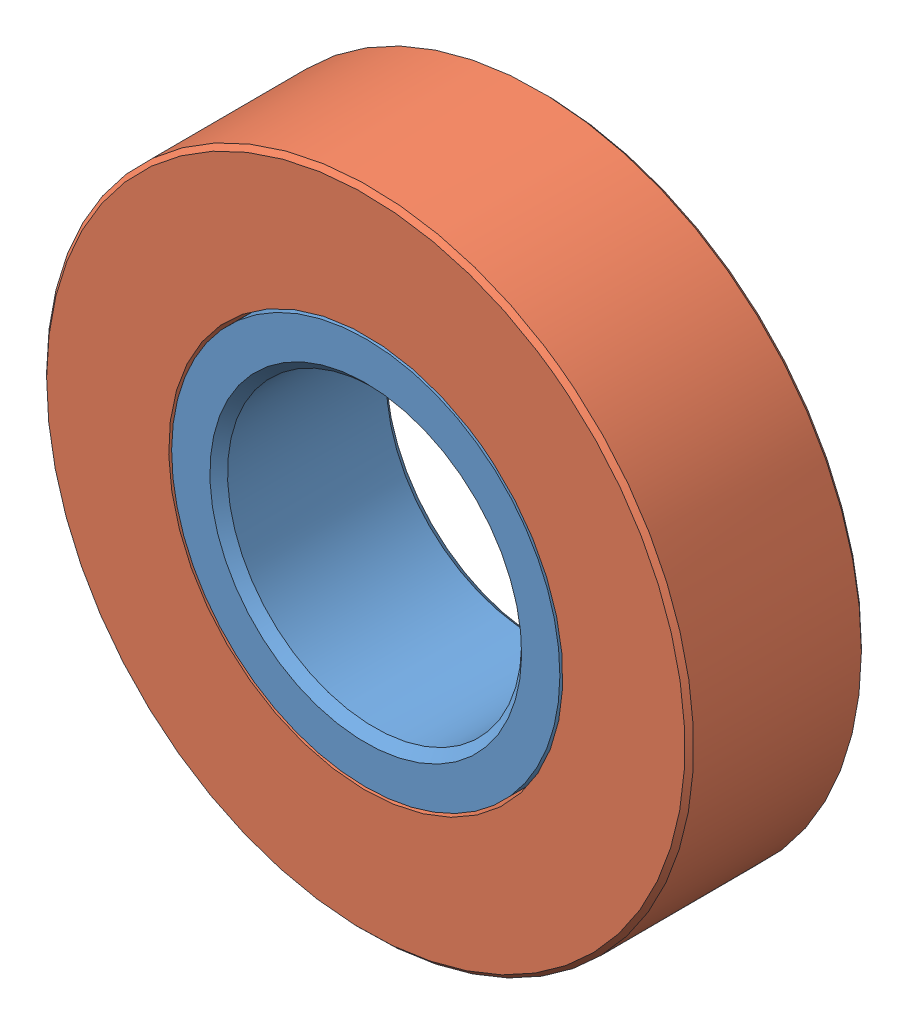
SolidWorks assembly Bearing, configuration Default. Lengths in mm.
Overall size (30.72 30.72 6).
2 component instances, 2 part files, 2 mates.
Components (placement in the parent):
- Bearing Inner-1: Bearing Inner [Default] at (5.4134 0 0) x (0.99329 0.115652 0) z (0 0 1) size (13.2 13.2 6)
- Bearing Outer-1: Bearing Outer [Default] at (5.4134 0 0) x (0.586238 0.810139 0) z (0 0 1) size (22 22 6)
Mates (geometry in assembly coordinates):
- Concentric1: concentric anti-aligned: circle of Bearing Inner-1; circle of Bearing Outer-1
- Coincident1: coincident aligned: plane of Bearing Inner-1 through (5.4134 0 3) normal (0 0 1); plane of Bearing Outer-1 through (5.4134 0 3) normal (0 0 1)
